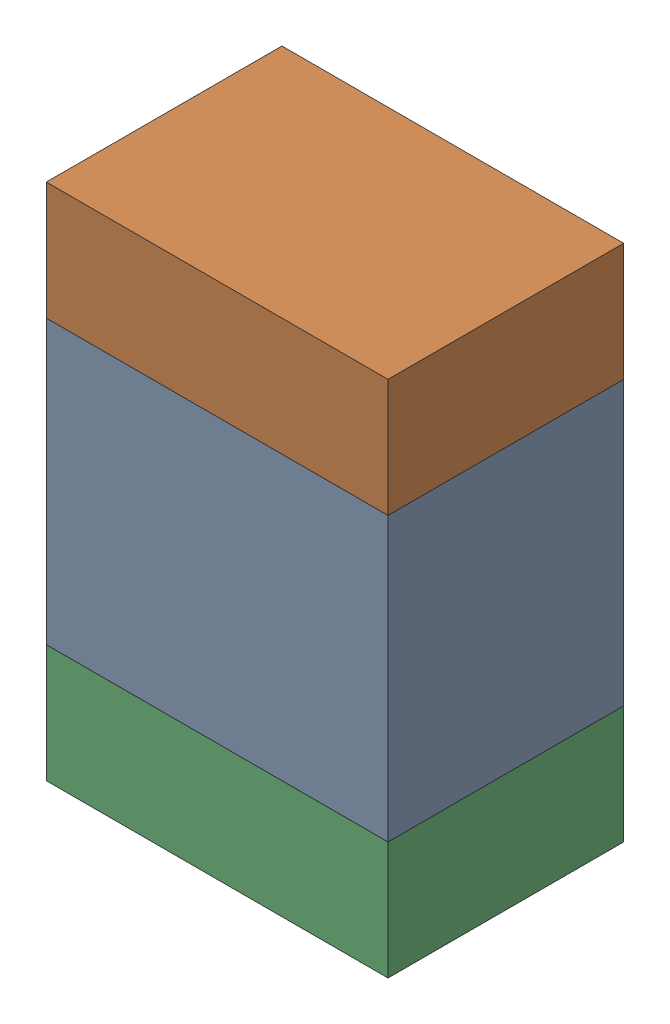
SolidWorks assembly C8, configuration Default. Lengths in mm.
Overall size (1.45 2.2 1).
6 component instances, 2 part files, 0 mates.
Components (placement in the parent):
- 959207984-1: 959207984 [Default] at (115.697 77.2073 0) size (1.45 1.2 1)
  - Extruded-18-1: Extruded-18 [Default] at origin size (1.45 1.2 1)
- 959207848-1: 959207848 [Default] at (115.697 78.0573 0) size (1.45 0.5 1)
  - Extruded-19-1: Extruded-19 [Default] at origin size (1.45 0.5 1)
- 959207848-2: 959207848 [Default] at (115.697 76.3573 0) size (1.45 0.5 1)
  - Extruded-19-1: Extruded-19 [Default] at origin size (1.45 0.5 1)
